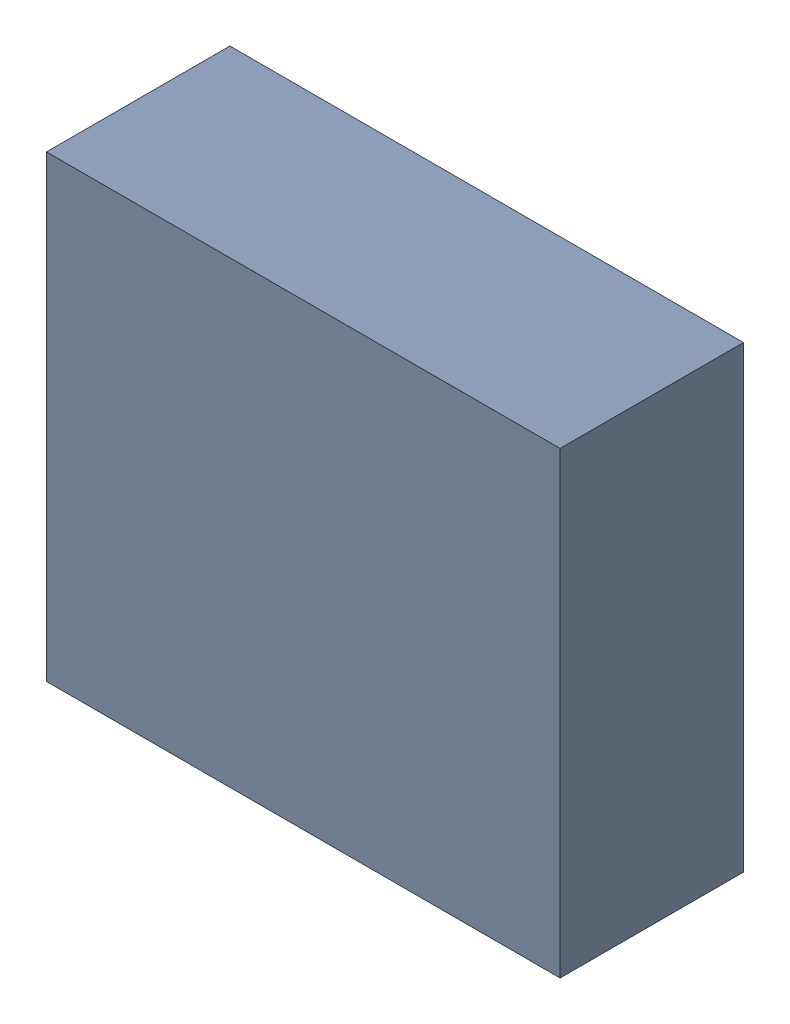
SolidWorks assembly L1, configuration ﾃﾞﾌｫﾙﾄ. Lengths in mm.
Overall size (11.2 10 4).
2 component instances, 1 part files, 0 mates.
Components (placement in the parent):
- 689265048-1: 689265048 [ﾃﾞﾌｫﾙﾄ] at (66 69 0) size (11.2 10 4)
  - Extruded_29-1: Extruded_29 [ﾃﾞﾌｫﾙﾄ] at origin size (11.2 10 4)
